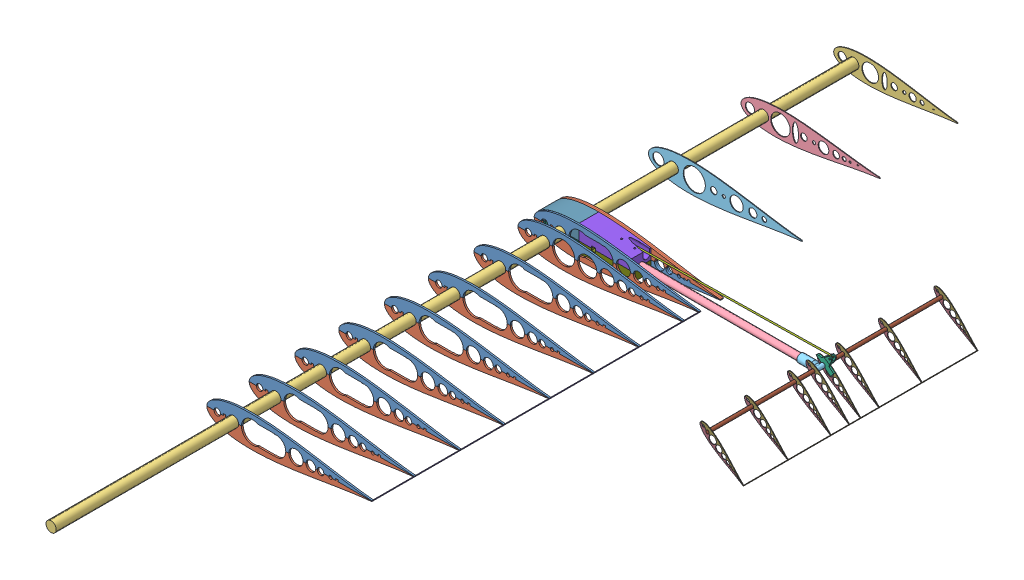
SolidWorks assembly Main Sail, configuration Default. Lengths in mm.
Overall size (1215.91 208.14 3131.82).
76 component instances, 23 part files, 45 mates.
Components (placement in the parent):
- Full Scale. Assembly Airfoil Servo Access-1: Full Scale. Assembly Airfoil Servo Access [Default] at (606.9035 405.2791 273.818) size (643.44 120.78 6.35)
  - Prototype rib mk 4 female-1: Prototype rib mk 4 female [Default] at (-578.6111 14.9076 101.6027) size (643.6 60.39 6.35)
  - Prototype rib mk 4 male-1: Prototype rib mk 4 male [Default] at (-578.6111 14.9076 101.6027) size (643.6 66.74 6.35)
- Mast-1: Mast [Default] at (132.4324 420.1867 2369.3208) x (-0.940836 0.338864 0) z (-0.338864 -0.940836 0) size (40 3131.82 40)
- Full Scale. Assembly Airfoil-1: Full Scale. Assembly Airfoil [Default] at (606.9035 405.2791 337.318) size (643.6 120.78 6.35)
  - Prototype rib mk 4 female-1: Prototype rib mk 4 female [Default] at (-578.6111 14.9076 101.6027) size (643.6 60.39 6.35)
  - Prototype rib mk 4 male-1: Prototype rib mk 4 male [Default] at (-578.6111 14.9076 101.6027) size (643.6 66.74 6.35)
- Full Scale. Assembly Airfoil-2: Full Scale. Assembly Airfoil [Default] at (606.9035 405.2791 508.768) size (643.6 120.78 6.35)
  - Prototype rib mk 4 female-1: Prototype rib mk 4 female [Default] at (-578.6111 14.9076 101.6027) size (643.6 60.39 6.35)
  - Prototype rib mk 4 male-1: Prototype rib mk 4 male [Default] at (-578.6111 14.9076 101.6027) size (643.6 66.74 6.35)
- Full Scale. Assembly Airfoil-3: Full Scale. Assembly Airfoil [Default] at (606.9035 405.2791 686.568) size (643.6 120.78 6.35)
  - Prototype rib mk 4 female-1: Prototype rib mk 4 female [Default] at (-578.6111 14.9076 101.6027) size (643.6 60.39 6.35)
  - Prototype rib mk 4 male-1: Prototype rib mk 4 male [Default] at (-578.6111 14.9076 101.6027) size (643.6 66.74 6.35)
- Full Scale. Assembly Airfoil-4: Full Scale. Assembly Airfoil [Default] at (606.9035 405.2791 858.018) size (643.6 120.78 6.35)
  - Prototype rib mk 4 female-1: Prototype rib mk 4 female [Default] at (-578.6111 14.9076 101.6027) size (643.6 60.39 6.35)
  - Prototype rib mk 4 male-1: Prototype rib mk 4 male [Default] at (-578.6111 14.9076 101.6027) size (643.6 66.74 6.35)
- Full Scale. Assembly Airfoil-5: Full Scale. Assembly Airfoil [Default] at (606.9035 405.2791 1035.818) size (643.6 120.78 6.35)
  - Prototype rib mk 4 female-1: Prototype rib mk 4 female [Default] at (-578.6111 14.9076 101.6027) size (643.6 60.39 6.35)
  - Prototype rib mk 4 male-1: Prototype rib mk 4 male [Default] at (-578.6111 14.9076 101.6027) size (643.6 66.74 6.35)
- Full Scale. Assembly Airfoil-6: Full Scale. Assembly Airfoil [Default] at (606.9035 405.2791 1207.268) size (643.6 120.78 6.35)
  - Prototype rib mk 4 female-1: Prototype rib mk 4 female [Default] at (-578.6111 14.9076 101.6027) size (643.6 60.39 6.35)
  - Prototype rib mk 4 male-1: Prototype rib mk 4 male [Default] at (-578.6111 14.9076 101.6027) size (643.6 66.74 6.35)
- Full Scale. Assembly Airfoil-7: Full Scale. Assembly Airfoil [Default] at (606.9035 405.2791 1385.068) size (643.6 120.78 6.35)
  - Prototype rib mk 4 female-1: Prototype rib mk 4 female [Default] at (-578.6111 14.9076 101.6027) size (643.6 60.39 6.35)
  - Prototype rib mk 4 male-1: Prototype rib mk 4 male [Default] at (-578.6111 14.9076 101.6027) size (643.6 66.74 6.35)
- Full Scale. Assembly Airfoil-8: Full Scale. Assembly Airfoil [Default] at (606.9035 405.2791 1550.168) size (643.6 120.78 6.35)
  - Prototype rib mk 4 female-1: Prototype rib mk 4 female [Default] at (-578.6111 14.9076 101.6027) size (643.6 60.39 6.35)
  - Prototype rib mk 4 male-1: Prototype rib mk 4 male [Default] at (-578.6111 14.9076 101.6027) size (643.6 66.74 6.35)
- Trim Tab-1: Trim Tab [Default] at (126.6675 420.5656 297.1585) x (1 0 0) z (0 1 0) size (1215.91 916.52 208.14)
  - Trim Tab Connector rod-1: Trim Tab Connector rod [Default] at (172.7333 -40.1622 -0.3772) x (0 -0.785901 0.618352) z (1 0 0) size (25.4 25.4 774.7)
  - Tab mast connector-1: Tab mast connector [Default] at (965.2133 -40.1622 -0.3772) x (-1 0 0) z (0 0 -1) size (77.47 35.56 32.36)
  - Push Pull Rod Connector Left Side-1: Push Pull Rod Connector Left Side [Default] at (959.2348 -14.6987 17.4744) x (0.77872 0 -0.627372) z (0 -1 0) size (118.86 59.06 18.8)
  - Rod-1: Rod [Default] at (153.6428 -12.3492 25.2502) x (0.016515 0 -0.999864) z (0.999864 0 0.016515) size (4.83 4.83 847.09)
  - H1S2-1: H1S2 [Default] at (-98.9704 -2.7675 0) x (1 0 0) z (0 1 0) size (277.53 60.37 76.2)
  - Servo Cap-1: Servo Cap [Default] at (78.7197 -18.6927 -77.0317) x (-0.082926 0 -0.996556) z (0.996556 0 -0.082926) size (61.69 13.97 62.71)
    - Servo Cap Lower Half-1: Servo Cap Lower Half [Default] at (-80.0498 3.6288 37.6188) size (43.18 7.62 43.18)
    - servo arm-1: servo arm [Default] at (-80.0498 -2.7212 37.6188) x (-0.693059 0 0.720881) z (-0.720881 0 -0.693059) size (56.49 13.97 20.96)
  - Trim tab mast-1: Trim tab mast [Default] at (965.2133 -15.6089 -0.3772) x (-0.588378 0 -0.808586) z (0.808586 0 -0.588378) size (12.7 914.4 12.7)
  - Assembly Trimtab Airfoil-1: Assembly Trimtab Airfoil [Default] at (1040.7235 16.4942 -58.8445) x (0.77872 0 -0.627372) z (0 -1 0) size (282.43 40.26 4.23)
    - Trim Tab Airfoil Full Female-1: Trim Tab Airfoil Full Female [Default] at (-297.8956 -20.5316 28.5466) size (281.79 38.82 4.23)
    - Trim Tab Airfoil Full Male-1: Trim Tab Airfoil Full Male [Default] at (-298.5353 16.6359 28.5476) size (282.43 38.64 4.23)
  - Assembly Trimtab Airfoil-2: Assembly Trimtab Airfoil [Default] at (1040.7235 -27.2784 -58.8445) x (0.77872 0 -0.627372) z (0 -1 0) size (282.43 40.26 4.23)
    - Trim Tab Airfoil Full Female-1: Trim Tab Airfoil Full Female [Default] at (-297.8956 -20.5316 28.5466) size (281.79 38.82 4.23)
    - Trim Tab Airfoil Full Male-1: Trim Tab Airfoil Full Male [Default] at (-298.5353 16.6359 28.5476) size (282.43 38.64 4.23)
  - Assembly Trimtab Airfoil-3: Assembly Trimtab Airfoil [Default] at (1040.7235 -440.0284 -58.8445) x (0.77872 0 -0.627372) z (0 -1 0) size (282.43 40.26 4.23)
    - Trim Tab Airfoil Full Female-1: Trim Tab Airfoil Full Female [Default] at (-297.8956 -20.5316 28.5466) size (281.79 38.82 4.23)
    - Trim Tab Airfoil Full Male-1: Trim Tab Airfoil Full Male [Default] at (-298.5353 16.6359 28.5476) size (282.43 38.64 4.23)
  - Assembly Trimtab Airfoil-4: Assembly Trimtab Airfoil [Default] at (1040.7235 -99.2451 -58.8445) x (0.77872 0 -0.627372) z (0 -1 0) size (282.43 40.26 4.23)
    - Trim Tab Airfoil Full Female-1: Trim Tab Airfoil Full Female [Default] at (-297.8956 -20.5316 28.5466) size (281.79 38.82 4.23)
    - Trim Tab Airfoil Full Male-1: Trim Tab Airfoil Full Male [Default] at (-298.5353 16.6359 28.5476) size (282.43 38.64 4.23)
  - Assembly Trimtab Airfoil-5: Assembly Trimtab Airfoil [Default] at (1040.7235 -266.4618 -58.8445) x (0.77872 0 -0.627372) z (0 -1 0) size (282.43 40.26 4.23)
    - Trim Tab Airfoil Full Female-1: Trim Tab Airfoil Full Female [Default] at (-297.8956 -20.5316 28.5466) size (281.79 38.82 4.23)
    - Trim Tab Airfoil Full Male-1: Trim Tab Airfoil Full Male [Default] at (-298.5353 16.6359 28.5476) size (282.43 38.64 4.23)
  - Assembly Trimtab Airfoil-6: Assembly Trimtab Airfoil [Default] at (1040.7235 88.4609 -58.8445) x (0.77872 0 -0.627372) z (0 -1 0) size (282.43 40.26 4.23)
    - Trim Tab Airfoil Full Female-1: Trim Tab Airfoil Full Female [Default] at (-297.8956 -20.5316 28.5466) size (281.79 38.82 4.23)
    - Trim Tab Airfoil Full Male-1: Trim Tab Airfoil Full Male [Default] at (-298.5353 16.6359 28.5476) size (282.43 38.64 4.23)
  - Assembly Trimtab Airfoil-7: Assembly Trimtab Airfoil [Default] at (1040.7235 255.6776 -58.8445) x (0.77872 0 -0.627372) z (0 -1 0) size (282.43 40.26 4.23)
    - Trim Tab Airfoil Full Female-1: Trim Tab Airfoil Full Female [Default] at (-297.8956 -20.5316 28.5466) size (281.79 38.82 4.23)
    - Trim Tab Airfoil Full Male-1: Trim Tab Airfoil Full Male [Default] at (-298.5353 16.6359 28.5476) size (282.43 38.64 4.23)
  - Assembly Trimtab Airfoil-8: Assembly Trimtab Airfoil [Default] at (1040.7235 472.2549 -58.8445) x (0.77872 0 -0.627372) z (0 -1 0) size (282.43 40.26 4.23)
    - Trim Tab Airfoil Full Female-1: Trim Tab Airfoil Full Female [Default] at (-297.8956 -20.5316 28.5466) size (281.79 38.82 4.23)
    - Trim Tab Airfoil Full Male-1: Trim Tab Airfoil Full Male [Default] at (-298.5353 16.6359 28.5476) size (282.43 38.64 4.23)
  - H1S1-1: H1S1 [Default] at (-99.7792 -2.7491 -0.0219) x (1 0 0) z (0 1 0) size (176.06 73.05 76.2)
  - H2S1-1: H2S1 [Default] at (-98.8831 -78.2622 -0.3789) x (1 0 0) z (0 -1 0) size (176.06 60.77 76.2)
  - H2S2-1: H2S2 [Default] at (-98.9704 -78.2622 -0.3772) x (1 0 0) z (0 -1 0) size (273.65 60.4 76.2)
- bottom support mast-1: bottom support mast [Default] at (671.1295 420.1867 1658.1208) x (0.999531 -0.030619 0) z (0.030619 0.999531 0) size (2.54 1282.7 2.54)
- trim tab support mast-1: trim tab support mast [Default] at (1231.3113 307.8568 769.9674) x (1 0 0) z (0 1 0) size (2.03 914.4 2.03)
- Servo Access Assembly-2: Servo Access Assembly [Default] at (356.2516 406.4353 280.8308) size (643.59 120.78 6.35)
  - Servo Access Full Size male-1: Servo Access Full Size male [Default] at (-327.9592 13.7514 12.04) size (643.59 66.74 6.35)
  - Servo Access Full Size-1: Servo Access Full Size [Default] at (-327.9592 13.7514 12.04) size (643.59 60.39 6.35)
- Servo Access Assembly-3: Servo Access Assembly [Default] at (356.2516 406.4353 274.4808) size (643.59 120.78 6.35)
  - Servo Access Full Size male-1: Servo Access Full Size male [Default] at (-327.9592 13.7514 12.04) size (643.59 66.74 6.35)
  - Servo Access Full Size-1: Servo Access Full Size [Default] at (-327.9592 13.7514 12.04) size (643.59 60.39 6.35)
- Airfoil 7 1 to 4-2: Airfoil 7 1 to 4 [Default] at (-230.0951 -114.2482 -762.4992) x (0.999999 -0.001141 0) z (0 0 1) size (483.52 90.94 2.54)
- Airfoil 5 1 to 4-1: Airfoil 5 1 to 4 [Default] at (-220.6899 -112.2977 -410.7092) x (0.999505 0.031468 0) z (0 0 1) size (541.46 101.69 2.54)
- Airfoil 3 1 to 4-1: Airfoil 3 1 to 4 [Default] at (-255.4897 -93.4379 -58.9192) x (0.999991 0.004308 0) z (0 0 1) size (598.33 112.32 2.54)
Mates (geometry in assembly coordinates):
- Concentric1: concentric anti-aligned: circle of Full Scale. Assembly Airfoil Servo Access-1/Prototype rib mk 4 male-1; circle of Mast-1
- Concentric2: concentric anti-aligned: circle of Mast-1; circle of ?
- Concentric3: concentric anti-aligned: circle of Mast-1; circle of ?
- Concentric4: concentric anti-aligned: circle of Mast-1; circle of ?
- Concentric5: concentric anti-aligned: circle of Mast-1; circle of ?
- Concentric6: concentric anti-aligned: circle of Mast-1; circle of ?
- Concentric7: concentric anti-aligned: circle of Mast-1; circle of ?
- Concentric8: concentric anti-aligned: circle of Mast-1; circle of ?
- Concentric9: concentric anti-aligned: circle of Mast-1; circle of ?
- Parallel16: parallel aligned: line of Full Scale. Assembly Airfoil Servo Access-1/Prototype rib mk 4 female-1 through (28.2924 420.1867 381.7708) axis (1 0 0); line of ? through (28.2924 420.1867 445.2708) axis (1 0 0)
- Parallel17: parallel aligned: line of ? through (28.2924 420.1867 445.2708) axis (1 0 0); line of ? through (28.2924 420.1867 616.7208) axis (1 0 0)
- Parallel18: parallel aligned: line of ? through (28.2924 420.1867 616.7208) axis (1 0 0); line of ? through (28.2924 420.1867 794.5208) axis (1 0 0)
- Parallel19: parallel aligned: line of ? through (28.2924 420.1867 794.5208) axis (1 0 0); line of ? through (28.2924 420.1867 965.9708) axis (1 0 0)
- Parallel20: parallel aligned: line of ? through (28.2924 420.1867 965.9708) axis (1 0 0); line of ? through (28.2924 420.1867 1143.7708) axis (1 0 0)
- Parallel21: parallel aligned: line of ? through (28.2924 420.1867 1143.7708) axis (1 0 0); line of ? through (28.2924 420.1867 1315.2208) axis (1 0 0)
- Parallel22: parallel aligned: line of ? through (28.2924 420.1867 1315.2208) axis (1 0 0); line of ? through (28.2924 420.1867 1493.0208) axis (1 0 0)
- Parallel23: parallel aligned: line of ? through (28.2924 420.1867 1493.0208) axis (1 0 0); line of ? through (28.2924 420.1867 1658.1208) axis (1 0 0)
- Concentric12: concentric anti-aligned: circle of Mast-1; circle of Trim Tab-1/H1S1-1
- Coincident26: coincident anti-aligned: plane of Full Scale. Assembly Airfoil Servo Access-1/Prototype rib mk 4 male-1 through (28.2924 420.1867 375.4208) normal (0 0 -1); plane of Trim Tab-1/H2S1-1 through (27.7844 420.1867 375.4208) normal (0 0 1)
- Concentric13: concentric anti-aligned: circle of Full Scale. Assembly Airfoil Servo Access-1/Prototype rib mk 4 female-1; circle of bottom support mast-1
- Coincident29: coincident aligned: plane of Full Scale. Assembly Airfoil Servo Access-1/Prototype rib mk 4 female-1 through (28.2924 420.1867 375.4208) normal (0 0 -1); plane of bottom support mast-1 through (671.1295 420.1867 375.4208) normal (0 0 -1)
- Coincident30: coincident aligned: plane of ? through (28.2924 420.1867 1658.1208) normal (0 0 1); plane of bottom support mast-1 through (671.1295 420.1867 1658.1208) normal (0 0 1)
- Concentric15: concentric anti-aligned: circle of Trim Tab-1/Assembly Trimtab Airfoil-8/Trim Tab Airfoil Full Female-1; circle of trim tab support mast-1
- Coincident34: coincident aligned: plane of Trim Tab-1/Assembly Trimtab Airfoil-8/Trim Tab Airfoil Full Female-1 through (1064.8488 441.9666 -144.4326) normal (0 0 -1); plane of trim tab support mast-1 through (1231.3113 307.8568 -144.4326) normal (0 0 -1)
- Concentric16: concentric anti-aligned: circle of Mast-1; circle of Servo Access Assembly-2/Servo Access Full Size-1
- Coincident35: coincident anti-aligned: plane of Trim Tab-1/H2S1-1 through (27.7844 420.1867 299.2208) normal (0 0 -1); plane of Servo Access Assembly-2/Servo Access Full Size male-1 through (28.2924 420.1867 299.2208) normal (0 0 1)
- Concentric17: concentric anti-aligned: circle of Mast-1; circle of Servo Access Assembly-3/Servo Access Full Size-1
- Coincident37: coincident anti-aligned: plane of Servo Access Assembly-2/Servo Access Full Size-1 through (28.2924 420.1867 292.8708) normal (0 0 -1); plane of Servo Access Assembly-3/Servo Access Full Size-1 through (28.2924 420.1867 292.8708) normal (0 0 1)
- Parallel27: parallel aligned: line of Servo Access Assembly-2/Servo Access Full Size male-1 through (28.2924 420.1867 299.2208) axis (0 0 -1); line of Servo Access Assembly-3/Servo Access Full Size male-1 through (28.2924 420.1867 292.8708) axis (0 0 -1)
- Concentric25: concentric anti-aligned: circle of Mast-1; circle of Airfoil 7 1 to 4-2
- Coincident45: coincident aligned: plane of Mast-1 through (132.4324 420.1867 -762.4992) normal (0 0 -1); plane of Airfoil 7 1 to 4-2 through (-230.0951 -114.2482 -762.4992) normal (0 0 -1)
- Concentric26: concentric anti-aligned: circle of Mast-1; circle of Airfoil 5 1 to 4-1
- Concentric27: concentric anti-aligned: circle of Mast-1; circle of Airfoil 3 1 to 4-1
- Distance1: distance = 349.25 mm anti-aligned: plane of Airfoil 5 1 to 4-1 through (-220.6899 -112.2977 -410.7092) normal (0 0 -1); plane of Airfoil 7 1 to 4-2 through (-230.0951 -114.2482 -759.9592) normal (0 0 1)
- Distance2: distance = 349.25 mm anti-aligned: plane of Airfoil 5 1 to 4-1 through (-220.6899 -112.2977 -408.1692) normal (0 0 1); plane of Airfoil 3 1 to 4-1 through (35.5831 419.7695 -58.9192) normal (0 0 -1)
- Distance3: distance = 342.9 mm anti-aligned: plane of Servo Access Assembly-3/Servo Access Full Size male-1 through (28.2924 420.1867 286.5208) normal (0 0 -1); plane of Airfoil 3 1 to 4-1 through (35.5831 419.7695 -56.3792) normal (0 0 1)
- Distance4: distance = 57.15 mm anti-aligned: plane of Full Scale. Assembly Airfoil Servo Access-1/Prototype rib mk 4 female-1 through (28.2924 420.1867 381.7708) normal (0 0 1); plane of ? through (28.2924 420.1867 438.9208) normal (0 0 -1)
- Distance5: distance = 165.1 mm anti-aligned: plane of ? through (28.2924 420.1867 445.2708) normal (0 0 1); plane of ? through (28.2924 420.1867 610.3708) normal (0 0 -1)
- Distance6: distance = 171.45 mm anti-aligned: plane of ? through (28.2924 420.1867 788.1708) normal (0 0 -1); plane of ? through (28.2924 420.1867 616.7208) normal (0 0 1)
- Distance7: distance = 165.1 mm anti-aligned: plane of ? through (28.2924 420.1867 794.5208) normal (0 0 1); plane of ? through (28.2924 420.1867 959.6208) normal (0 0 -1)
- Distance9: distance = 171.45 mm anti-aligned: plane of ? through (28.2924 420.1867 965.9708) normal (0 0 1); plane of ? through (28.2924 420.1867 1137.4208) normal (0 0 -1)
- Distance10: distance = 165.1 mm anti-aligned: plane of ? through (28.2924 420.1867 1308.8708) normal (0 0 -1); plane of ? through (28.2924 420.1867 1143.7708) normal (0 0 1)
- Distance11: distance = 171.45 mm anti-aligned: plane of ? through (28.2924 420.1867 1315.2208) normal (0 0 1); plane of ? through (28.2924 420.1867 1486.6708) normal (0 0 -1)
- Parallel34: parallel anti-aligned: line of Trim Tab-1/H2S1-1 through (113.3824 420.1867 299.2208) axis (-1 0 0); line of Servo Access Assembly-3/Servo Access Full Size-1 through (28.2924 420.1867 286.5208) axis (1 0 0)
- Parallel35: parallel anti-aligned: line of Full Scale. Assembly Airfoil Servo Access-1/Prototype rib mk 4 male-1 through (28.2924 420.1867 381.7708) axis (1 0 0); line of Trim Tab-1/H2S1-1 through (113.3824 420.1867 299.2208) axis (-1 0 0)
